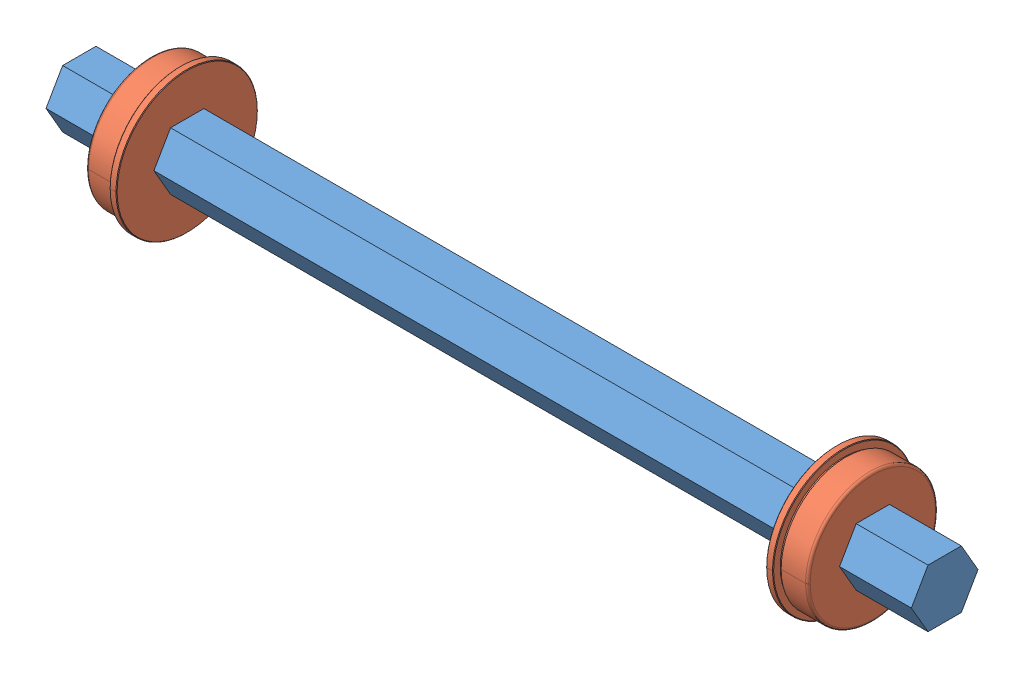
SolidWorks assembly RotatingBar, configuration Default. Lengths in mm.
Overall size (190.5 31.11 31.12).
3 component instances, 2 part files, 6 mates.
Components (placement in the parent):
- 1_5_IN_HEX_SHAFT-1: 1_5_IN_HEX_SHAFT [Default] at (-30.7111 97.366 151.0827) size (190.5 12.7 14.66)
- am-2986 FR8ZZ Hex Bearing-1: am-2986 FR8ZZ Hex Bearing [Default] at (143.9673 97.366 151.0827) x (0 0 1) z (-1 0 0) size (31.12 31.12 7.93)
- am-2986 FR8ZZ Hex Bearing-2: am-2986 FR8ZZ Hex Bearing [Default] at (-14.8894 97.366 151.0827) x (0 0 -1) z (1 0 0) size (31.12 31.12 7.93)
Mates (geometry in assembly coordinates):
- Coincident1: coincident anti-aligned: plane of 1_5_IN_HEX_SHAFT-1 through (159.7889 100.541 156.5819) normal (0 0.5 0.866025); plane of am-2986 FR8ZZ Hex Bearing-2 through (-16.4337 97.366 158.415) normal (0 -0.5 -0.866025)
- Coincident2: coincident anti-aligned: plane of 1_5_IN_HEX_SHAFT-1 through (159.7889 94.191 156.5819) normal (0 -0.5 0.866025); plane of am-2986 FR8ZZ Hex Bearing-2 through (-16.4337 91.016 154.7488) normal (0 0.5 -0.866025)
- Coincident3: coincident anti-aligned: plane of 1_5_IN_HEX_SHAFT-1 through (159.7889 94.191 145.5834) normal (0 -0.5 -0.866025); plane of am-2986 FR8ZZ Hex Bearing-1 through (126.5683 91.016 147.4165) normal (0 0.5 0.866025)
- Coincident4: coincident anti-aligned: plane of 1_5_IN_HEX_SHAFT-1 through (159.7889 103.716 151.0827) normal (0 1 0); plane of am-2986 FR8ZZ Hex Bearing-1 through (126.5683 103.716 147.4165) normal (0 -1 0)
- Distance1: distance = 146.05 mm anti-aligned: plane of am-2986 FR8ZZ Hex Bearing-1 through (137.5639 97.366 165.0527) normal (1 0 0); plane of am-2986 FR8ZZ Hex Bearing-2 through (-8.4861 97.366 137.1127) normal (-1 0 0)
- Distance2: distance = 15.8217 mm aligned: plane of 1_5_IN_HEX_SHAFT-1 through (-30.7111 97.366 151.0827) normal (-1 0 0); plane of am-2986 FR8ZZ Hex Bearing-2 through (-14.8894 97.366 151.0827) normal (-1 0 0)
